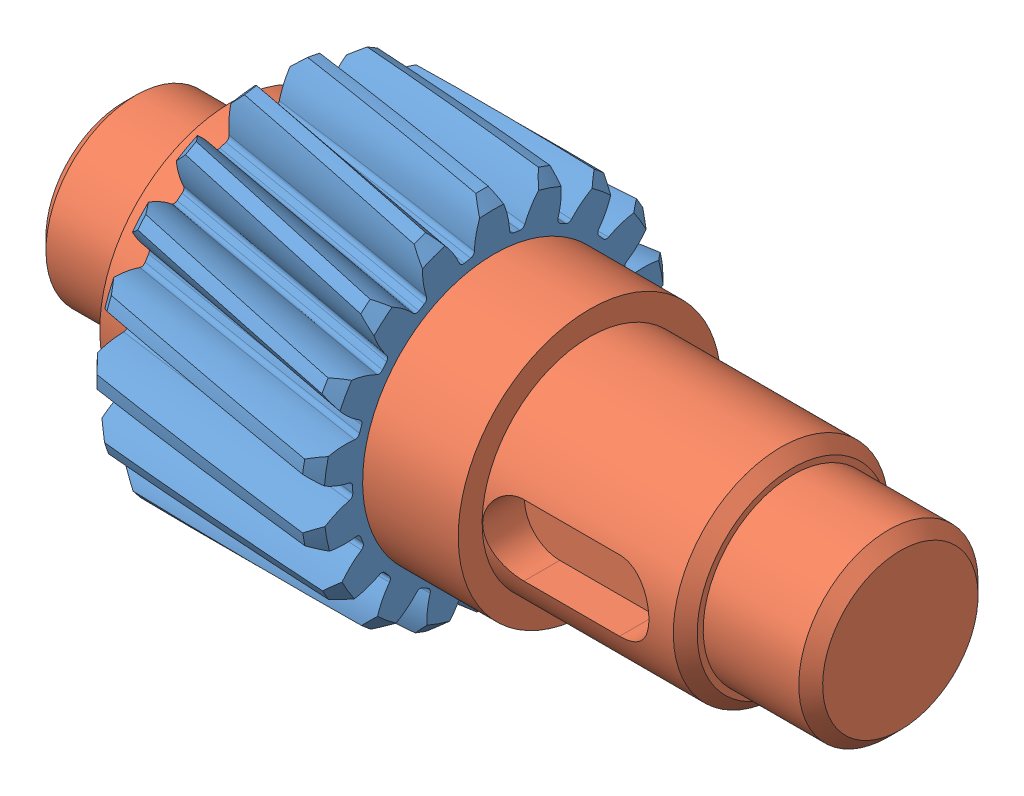
SolidWorks assembly second pinion, configuration Default. Lengths in mm.
Overall size (65 41.93 41.93).
3 component instances, 3 part files, 4 mates.
Components (placement in the parent):
- helical gear_3_am-1: helical gear_3_am [second pinion] at (28.0817 5.1613 0) x (1 0 0) z (0 0.849872 -0.52699) size (19 30.45 30.45)
- Part1^second pinion-1: Part1^second pinion [Default] at origin (virtual)
- second pinion shaft-1: second pinion shaft [Default] at (16.0817 5.1613 0) x (0 1 0) z (0 0 1) size (22 65 22)
Mates (geometry in assembly coordinates):
- Coincident2: coincident: line of helical gear_3_am-1 through (17.0835 46.1235 5.1613) axis (0 -1 0)
- Distance1: distance = 15.25 mm: line of assembly; line of assembly; axis of helical gear_3_am-1 through (17.0835 46.1235 5.1613) axis (0 -1 0)
- Coincident4: coincident anti-aligned: line of helical gear_3_am-1 through (19 47.0817 5.1613) axis (0 -1 0); line of second pinion shaft-1 through (30 25.0817 5.1613) axis (0 1 0)
- Distance2: distance = 12 mm aligned: plane of second pinion shaft-1 through (16.0817 5.1613 0) normal (-1 0 0); plane of helical gear_3_am-1 through (28.0817 5.1613 0) normal (-1 0 0)
